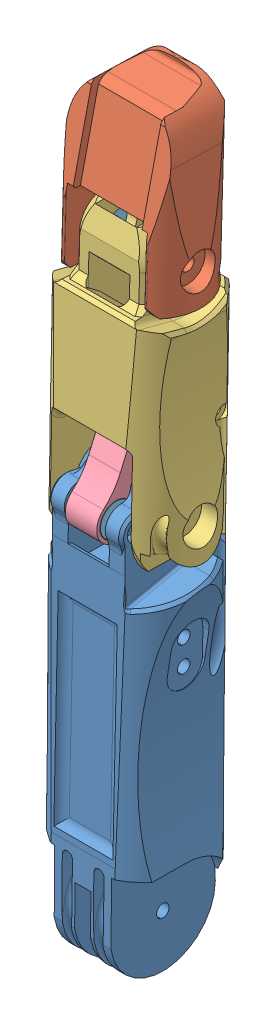
SolidWorks assembly assembly index finger, configuration Default. Lengths in mm.
Overall size (26.44 120.35 20.02).
12 component instances, 5 part files, 24 mates.
Components (placement in the parent):
- index link3-1: index link3 [Default] at (0 -18.7693 -24.4827) x (1 0 0) z (0 0.008727 0.999962) size (26.44 68.68 19.38)
- index link1-1: index link1 [Default] at (0 70.8122 -25.6293) x (1 0 0) z (0 0.02853 0.999593) size (19.5 27.22 13.31)
- index link2-1: index link2 [Default] at (0 36.5986 -24.9659) x (1 0 0) z (0 0.019387 0.999812) size (23.71 44.22 15.32)
- index linkage-1: index linkage [Default] at (0 52.954 -25.2673) x (1 0 0) z (0 0.999831 -0.018409) size (5 17.7 37.17)
- bearing 1.5-4-5-2-1: bearing 1.5-4-5-2 [Default] at (-0.5 67.4029 -31.1634) x (0 1 0) z (0 0 1) size (5 2 5)
- bearing 1.5-4-5-2-2: bearing 1.5-4-5-2 [Default] at (0.5 67.4029 -31.1634) x (0 -0.870554 0.492072) z (0 0.492072 0.870554) size (5 2 5)
- bearing 1.5-4-5-2-3: bearing 1.5-4-5-2 [Default] at (4.35 70.8122 -25.6293) x (0 -0.870554 0.492072) z (0 0.492072 0.870554) size (5 2 5)
- bearing 1.5-4-5-2-4: bearing 1.5-4-5-2 [Default] at (-4.35 70.8122 -25.6293) x (0 1 0) z (0 0 1) size (5 2 5)
- bearing 1.5-4-5-2-5: bearing 1.5-4-5-2 [Default] at (-4.35 36.5986 -24.9659) x (0 0.978691 -0.205336) z (0 0.205336 0.978691) size (5 2 5)
- bearing 1.5-4-5-2-6: bearing 1.5-4-5-2 [Default] at (4.35 36.5986 -24.9659) x (0 -0.870554 0.492072) z (0 0.492072 0.870554) size (5 2 5)
- bearing 1.5-4-5-2-7: bearing 1.5-4-5-2 [Default] at (0.5 36.6499 -19.0961) x (0 -0.870554 0.492072) z (0 0.492072 0.870554) size (5 2 5)
- bearing 1.5-4-5-2-8: bearing 1.5-4-5-2 [Default] at (-0.5 36.6499 -19.0961) x (0 0.978691 -0.205336) z (0 0.205336 0.978691) size (5 2 5)
Mates (geometry in assembly coordinates):
- Concentric1: concentric: cylinder of assembly; cylinder of assembly; cylinder of index link3-1 through (-10.4 36.5986 -24.9659) axis (1 0 0) radius 2.55; cylinder of index link2-1 through (7.4 36.5986 -24.9659) axis (1 0 0) radius 2.75
- Width1: width: plane of assembly; plane of assembly; plane of assembly; plane of assembly; plane of index link2-1 through (-6.4 48.4781 -31.2974) normal (1 0 0); plane of index link2-1 through (6.4 48.4781 -31.2974) normal (-1 0 0); plane of index link3-1 through (-5.75 31.2988 -24.9196) normal (-1 0 0); plane of index link3-1 through (5.75 31.2988 -24.9196) normal (1 0 0)
- Concentric2: concentric: cylinder of assembly; cylinder of assembly; cylinder of index link1-1 through (-10.0932 70.8122 -25.6293) axis (1 0 0) radius 1; cylinder of index link2-1 through (-10.4 70.8122 -25.6293) axis (1 0 0) radius 2.55
- Width2: width: plane of assembly; plane of assembly; plane of assembly; plane of assembly; plane of index link1-1 through (-6.4 99.7255 -26.4545) normal (1 0 0); plane of index link1-1 through (6.4 99.7255 -26.4545) normal (-1 0 0); plane of index link2-1 through (-5.75 65.5132 -25.5265) normal (-1 0 0); plane of index link2-1 through (5.75 65.5132 -25.5265) normal (1 0 0)
- Concentric3: concentric: cylinder of assembly; cylinder of assembly; cylinder of index link3-1 through (-10.8126 36.6499 -19.0961) axis (1 0 0) radius 0.65; cylinder of index linkage-1 through (2.5 36.6499 -19.0961) axis (-1 0 0) radius 2.075
- Width3: width: plane of assembly; plane of assembly; plane of assembly; plane of assembly; plane of index link3-1 through (-3.25 -23.8223 -30.5388) normal (1 0 0); plane of index link3-1 through (3.25 -23.8223 -30.5388) normal (-1 0 0); plane of index linkage-1 through (-2.5 52.954 -25.2673) normal (-1 0 0); plane of index linkage-1 through (2.5 52.954 -25.2673) normal (1 0 0)
- Concentric4: concentric: cylinder of assembly; cylinder of assembly; cylinder of index link1-1 through (-10.0465 67.4029 -31.1634) axis (1 0 0) radius 0.7; cylinder of index linkage-1 through (2.5 67.4029 -31.1634) axis (-1 0 0) radius 2.075
- Coincident1: coincident: plane of assembly through (0 0 0) normal (1 0 0); plane of index link3-1 through (0 -18.7693 -24.4827) normal (1 0 0); plane of assembly
- Concentric6: concentric: cylinder of assembly; cylinder of assembly; cylinder of index linkage-1 through (2.5 67.4029 -31.1634) axis (-1 0 0) radius 2.075; cylinder of bearing 1.5-4-5-2-1 through (-2.5 67.4029 -31.1634) axis (1 0 0) radius 2
- Coincident2: coincident: plane of assembly; plane of assembly; plane of index linkage-1 through (-1.9 67.4029 -31.1634) normal (-1 0 0); plane of bearing 1.5-4-5-2-1 through (-1.9 67.4029 -31.1634) normal (1 0 0)
- Concentric7: concentric: cylinder of assembly; cylinder of assembly; cylinder of index linkage-1 through (2.5 67.4029 -31.1634) axis (-1 0 0) radius 2.075; cylinder of bearing 1.5-4-5-2-2 through (2.5 67.4029 -31.1634) axis (-1 0 0) radius 2
- Coincident3: coincident: plane of assembly; plane of assembly; plane of index linkage-1 through (1.9 67.4029 -31.1634) normal (1 0 0); plane of bearing 1.5-4-5-2-2 through (1.9 67.4029 -31.1634) normal (-1 0 0)
- Concentric8: concentric: cylinder of assembly; cylinder of assembly; cylinder of index link2-1 through (-10.4 70.8122 -25.6293) axis (1 0 0) radius 2.55; cylinder of bearing 1.5-4-5-2-3 through (6.35 70.8122 -25.6293) axis (-1 0 0) radius 2
- Coincident4: coincident: plane of assembly; plane of assembly; plane of index link2-1 through (5.75 65.5132 -25.5265) normal (1 0 0); plane of bearing 1.5-4-5-2-3 through (5.75 70.8122 -25.6293) normal (-1 0 0)
- Concentric9: concentric: cylinder of assembly; cylinder of assembly; cylinder of index link2-1 through (-10.4 70.8122 -25.6293) axis (1 0 0) radius 2.55; cylinder of bearing 1.5-4-5-2-4 through (-6.35 70.8122 -25.6293) axis (1 0 0) radius 2
- Coincident5: coincident: plane of assembly; plane of assembly; plane of index link2-1 through (-5.75 65.5132 -25.5265) normal (-1 0 0); plane of bearing 1.5-4-5-2-4 through (-5.75 70.8122 -25.6293) normal (1 0 0)
- Concentric10: concentric: cylinder of assembly; cylinder of assembly; cylinder of index link3-1 through (-10.4 36.5986 -24.9659) axis (1 0 0) radius 2.55; cylinder of bearing 1.5-4-5-2-5 through (-6.35 36.5986 -24.9659) axis (1 0 0) radius 2
- Coincident6: coincident: plane of assembly; plane of assembly; plane of index link3-1 through (-5.75 31.2988 -24.9196) normal (-1 0 0); plane of bearing 1.5-4-5-2-5 through (-5.75 36.5986 -24.9659) normal (1 0 0)
- Concentric11: concentric: cylinder of assembly; cylinder of assembly; cylinder of index link3-1 through (-10.4 36.5986 -24.9659) axis (1 0 0) radius 2.55; cylinder of bearing 1.5-4-5-2-6 through (6.35 36.5986 -24.9659) axis (-1 0 0) radius 2
- Coincident7: coincident: plane of assembly; plane of assembly; plane of index link3-1 through (5.75 31.2988 -24.9196) normal (1 0 0); plane of bearing 1.5-4-5-2-6 through (5.75 36.5986 -24.9659) normal (-1 0 0)
- Concentric12: concentric: cylinder of assembly; cylinder of assembly; cylinder of index link3-1 through (-10.8126 36.6499 -19.0961) axis (1 0 0) radius 0.65; cylinder of bearing 1.5-4-5-2-7 through (2.5 36.6499 -19.0961) axis (-1 0 0) radius 2
- Coincident8: coincident: plane of assembly; plane of assembly; plane of index linkage-1 through (1.9 36.6499 -19.0961) normal (1 0 0); plane of bearing 1.5-4-5-2-7 through (1.9 36.6499 -19.0961) normal (-1 0 0)
- Concentric13: concentric: cylinder of assembly; cylinder of assembly; cylinder of index link3-1 through (-10.8126 36.6499 -19.0961) axis (1 0 0) radius 0.65; cylinder of bearing 1.5-4-5-2-8 through (-2.5 36.6499 -19.0961) axis (1 0 0) radius 2
- Coincident9: coincident: plane of assembly; plane of assembly; plane of index linkage-1 through (-1.9 36.6499 -19.0961) normal (-1 0 0); plane of bearing 1.5-4-5-2-8 through (-1.9 36.6499 -19.0961) normal (1 0 0)
